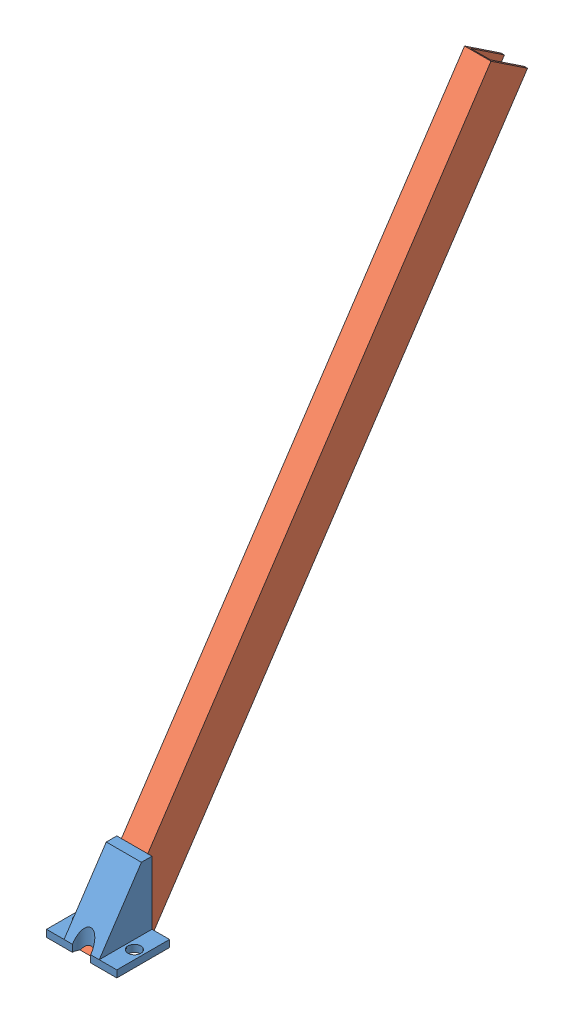
SolidWorks assembly ConnectBowlDescrambler, configuration Default. Lengths in mm.
Overall size (25.4 220.15 156.23).
2 component instances, 2 part files, 2 mates.
Components (placement in the parent):
- RampHolder-1: RampHolder [Default] at (-4.0903 4.976 32.2828) size (25.4 25.4 19.05)
- JawTrack-1: JawTrack [9001K707] at (8.6732 110.6464 -40.2866) x (-1 0 0) z (0 -0.83205 0.5547) size (9.53 15.88 254)
Mates (geometry in assembly coordinates):
- Coincident1: coincident anti-aligned: plane of RampHolder-1 through (-4.0903 3.9964 30.8134) normal (0 -0.5547 -0.83205); plane of JawTrack-1 through (13.4357 4.976 30.1603) normal (0 0.5547 0.83205)
- Coincident3: coincident anti-aligned: plane of RampHolder-1 through (13.4357 19.8758 -7.2472) normal (-1 0 0); plane of JawTrack-1 through (13.4357 -3.8298 16.9515) normal (1 0 0)
